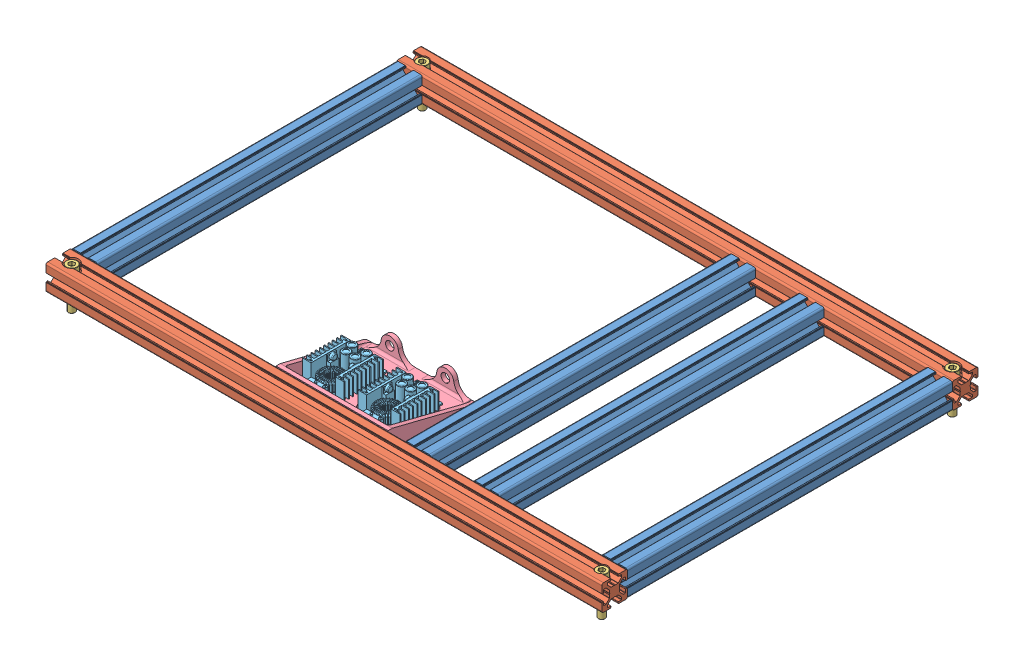
SolidWorks assembly Frame, configuration Default. Lengths in mm.
Overall size (650 51 440).
13 component instances, 5 part files, 32 mates.
Components (placement in the parent):
- Frame_profile_short-1: Frame_profile_short [Default] at origin size (30 30 380)
- Frame_profile-1: Frame_profile [Default] at (-15 0 395) x (0 0 -1) z (1 0 0) size (30 30 650)
- Frame_profile-2: Frame_profile [Default] at (635 0 -15) x (0 0 1) z (-1 0 0) size (30 30 650)
- Frame_profile_short-2: Frame_profile_short [Default] at (620 0 0) size (30 30 380)
- Frame_profile_short-3: Frame_profile_short [Default] at (470 0 0) size (30 30 380)
- Frame_profile_short-4: Frame_profile_short [Default] at (390 0 0) size (30 30 380)
- socket head cap screw_iso-10: socket head cap screw_iso [ISO 4762 M8 x 40 - 40N] at (0 14 -15) x (0 -1 0) z (0 0 1) size (48 13 13)
- socket head cap screw_iso-11: socket head cap screw_iso [ISO 4762 M8 x 40 - 40N] at (0 14 395) x (0 -1 0) z (0.186343 0 0.982485) size (48 13 13)
- socket head cap screw_iso-12: socket head cap screw_iso [ISO 4762 M8 x 40 - 40N] at (620 14 395) x (0 -1 0) z (0 0 1) size (48 13 13)
- socket head cap screw_iso-13: socket head cap screw_iso [ISO 4762 M8 x 40 - 40N] at (620 14 -15) x (0 -1 0) z (0 0 1) size (48 13 13)
- Converter_box-1: Converter_box [Default] at (289.5 -15 334) size (131 30 105)
- Converter-1: Converter [00] at (257 -3.5 334) size (49 24 65)
- Converter-2: Converter [00] at (322 -3.5 334) size (49 24 65)
Mates (geometry in assembly coordinates):
- Coincident1: coincident: plane of Frame_profile_short-1 through (-13.1 4.4 0) normal (0 0 -1); plane of Frame_profile-2 through (-15 4.8 0) normal (0 0 1)
- Coincident2: coincident: plane of Frame_profile_short-1 through (-13.1 4.4 380) normal (0 0 1); plane of Frame_profile-1 through (635 4.8 380) normal (0 0 -1)
- Coincident3: coincident: plane of Frame_profile_short-1 through (-15 13 380) normal (-1 0 0); plane of Frame_profile-2 through (-15 4.4 -28.1) normal (-1 0 0)
- Coincident4: coincident: plane of Frame_profile_short-1 through (13 15 380) normal (0 1 0); plane of Frame_profile-2 through (-15 15 -2) normal (0 1 0)
- Coincident5: coincident: plane of Frame_profile_short-1 through (-4.8 15 380) normal (0 1 0); plane of Frame_profile-1 through (635 15 382) normal (0 1 0)
- Coincident6: coincident: plane of Frame_profile_short-1 through (-15 13 380) normal (-1 0 0); plane of Frame_profile-1 through (-15 4.4 408.1) normal (-1 0 0)
- Coincident8: coincident: plane of Frame_profile-2 through (-15 15 -2) normal (0 1 0); plane of Frame_profile_short-2 through (615.2 15 380) normal (0 1 0)
- Coincident9: coincident: plane of Frame_profile-1 through (635 -13 380) normal (0 0 -1); plane of Frame_profile_short-2 through (606.9 4.4 380) normal (0 0 1)
- Coincident10: coincident: plane of Frame_profile-1 through (635 4.4 408.1) normal (1 0 0); plane of Frame_profile_short-2 through (635 4.8 380) normal (1 0 0)
- Coincident12: coincident: plane of Frame_profile-1 through (635 15 382) normal (0 1 0); plane of Frame_profile_short-4 through (385.2 15 380) normal (0 1 0)
- Coincident13: coincident: plane of Frame_profile-1 through (635 4.8 380) normal (0 0 -1); plane of Frame_profile_short-4 through (376.9 4.4 380) normal (0 0 1)
- Coincident14: coincident: plane of Frame_profile-1 through (635 15 382) normal (0 1 0); plane of Frame_profile_short-3 through (465.2 15 380) normal (0 1 0)
- Coincident15: coincident: plane of Frame_profile-1 through (635 4.8 380) normal (0 0 -1); plane of Frame_profile_short-3 through (456.9 4.4 380) normal (0 0 1)
- Distance1: distance = 120 mm: plane of Frame_profile_short-3 through (485 -13 380) normal (1 0 0); plane of Frame_profile_short-2 through (605 -4.8 380) normal (-1 0 0)
- Distance2: distance = 50 mm: plane of Frame_profile_short-4 through (405 4.8 380) normal (1 0 0); plane of Frame_profile_short-3 through (455 13 380) normal (-1 0 0)
- Concentric7: concentric: cylinder of Frame_profile-2 through (0 -15 -15) axis (0 1 0) radius 4; cylinder of socket head cap screw_iso-10 through (0 45.75 -15) axis (0 1 0) radius 6.5
- Coincident24: coincident: plane of Frame_profile-2 through (-15 6 -11.0456) normal (0 1 0); plane of socket head cap screw_iso-10 through (6.5 6 -15) normal (0 -1 0)
- Concentric8: concentric: cylinder of Frame_profile-1 through (0 -15 395) axis (0 1 0) radius 4; cylinder of socket head cap screw_iso-11 through (0 45.75 395) axis (0 1 0) radius 6.5
- Coincident25: coincident: plane of Frame_profile-1 through (635 6 395.934) normal (0 1 0); plane of socket head cap screw_iso-11 through (6.3862 6 393.7888) normal (0 -1 0)
- Concentric9: concentric: cylinder of Frame_profile-1 through (620 -15 395) axis (0 1 0) radius 4; cylinder of socket head cap screw_iso-12 through (620 45.75 395) axis (0 1 0) radius 6.5
- Coincident26: coincident: plane of Frame_profile-1 through (635 6 395.934) normal (0 1 0); plane of socket head cap screw_iso-12 through (626.5 6 395) normal (0 -1 0)
- Concentric10: concentric: cylinder of Frame_profile-2 through (620 -15 -15) axis (0 1 0) radius 4; cylinder of socket head cap screw_iso-13 through (620 45.75 -15) axis (0 1 0) radius 6.5
- Coincident27: coincident: plane of Frame_profile-2 through (-15 6 -11.0456) normal (0 1 0); plane of socket head cap screw_iso-13 through (626.5 6 -15) normal (0 -1 0)
- Coincident28: coincident: plane of Frame_profile-1 through (635 4.8 380) normal (0 0 -1); plane of Converter_box-1 through (289.5 -15 380) normal (0 0 1)
- Coincident29: coincident: plane of Frame_profile-1 through (635 15 382) normal (0 1 0); plane of Converter_box-1 through (224 15 380) normal (0 1 0)
- Distance3: distance = 20 mm: plane of Frame_profile_short-4 through (375 13 380) normal (-1 0 0); plane of Converter_box-1 through (355 -10 275) normal (1 0 0)
- Concentric11: concentric: cylinder of Converter_box-1 through (270.25 -10 304.75) axis (0 -1 0) radius 1.2; cylinder of Converter-1 through (270.25 -5 304.75) axis (0 1 0) radius 1.6
- Coincident31: coincident: plane of Converter_box-1 through (270.25 -5 304.75) normal (0 1 0); plane of Converter-1 through (257 -5 334) normal (0 -1 0)
- Concentric12: concentric: cylinder of Converter_box-1 through (243.75 -5 304.75) axis (0 -1 0) radius 1.2; cylinder of Converter-1 through (243.75 -5 304.75) axis (0 1 0) radius 1.6
- Coincident32: coincident: plane of Converter_box-1 through (308.75 -5 304.75) normal (0 1 0); plane of Converter-2 through (322 -5 334) normal (0 -1 0)
- Concentric13: concentric: circle of Converter_box-1; cylinder of Converter-2 through (308.75 -5 304.75) axis (0 1 0) radius 1.6
- Concentric14: concentric: cylinder of Converter_box-1 through (335.25 -10 304.75) axis (0 -1 0) radius 1.2; cylinder of Converter-2 through (335.25 -5 304.75) axis (0 1 0) radius 1.6
